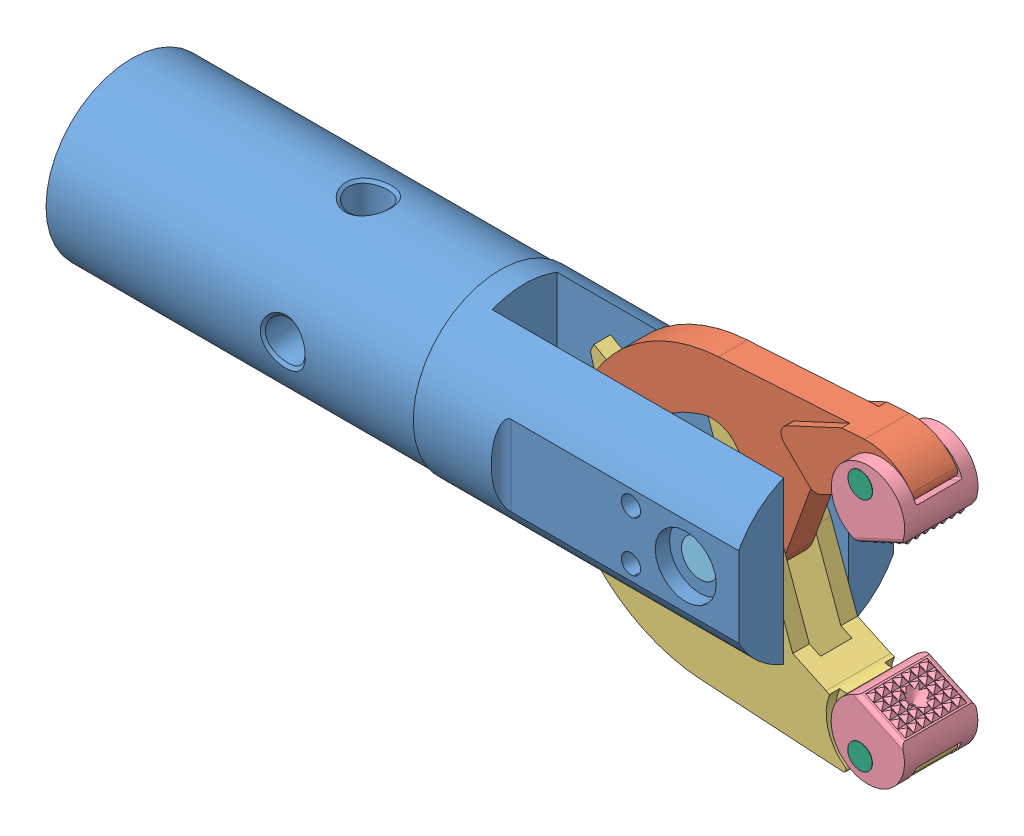
SolidWorks assembly Ensamblaje 2 Pieza 2 Tarea 2, configuration Predeterminado. Lengths in mm.
Overall size (215.83 114.08 45.21).
8 component instances, 6 part files, 19 mates.
Components (placement in the parent):
- T02 EJER02 Body-1: T02 EJER02 Body [Default] at origin size (177.75 45.21 45.21)
- T02 EJER02 Arm1-1: T02 EJER02 Arm1 [Default] at (-13.7795 0 0) x (-0.906308 -0.422618 0) z (0 0 -1) size (103 45.53 11.68)
- T02 EJER02 Arm2-1: T02 EJER02 Arm2 [Default] at (-13.7795 0 0) x (-0.906308 0.422618 0) z (0 0 1) size (103 45.53 16.81)
- T02 EJER02 Grip-1: T02 EJER02 Grip [Default] at (22.9957 26.313 -0.0254) x (0 0 -1) z (0.906308 0.422618 0) size (19.05 17.93 19.05)
- T02 EJER02 Large_Pin-1: T02 EJER02 Large_Pin [Default] at (-13.7795 0 -0.127) size (9.53 9.53 32.77)
- T02 EJER02 Small_Pin-1: T02 EJER02 Small_Pin [Default] at (21.0098 30.5717 0.1746) size (6.35 6.35 19.16)
- T02 EJER02 Grip-2: T02 EJER02 Grip [Default] at (22.9957 -26.313 0.0254) x (0 0 1) z (0.906308 -0.422618 0) size (19.05 17.93 19.05)
- T02 EJER02 Small_Pin-2: T02 EJER02 Small_Pin [Default] at (21.0098 -30.5717 0.2254) size (6.35 6.35 19.16)
Mates (geometry in assembly coordinates):
- Coincidente1: coordinate: point of T02 EJER02 Body-1
- Coincidente4: coincident anti-aligned: plane of T02 EJER02 Body-1 through (-75.692 -22.606 8.4074) normal (0 0 -1); plane of T02 EJER02 Arm2-1 through (21.091 -63.9042 8.4074) normal (0 0 1)
- Concéntrica4: concentric aligned: circle of T02 EJER02 Body-1; circle of T02 EJER02 Arm2-1
- Concéntrica9: concentric anti-aligned: cylinder of T02 EJER02 Arm1-1 through (-13.7795 0 5.842) axis (0 0 -1) radius 4.7688; cylinder of T02 EJER02 Arm2-1 through (-13.7795 0 -8.4074) axis (0 0 1) radius 4.7688
- Ancho8: width aligned: plane of T02 EJER02 Arm2-1 through (21.091 -63.9042 4.0894) normal (0 0 -1); plane of T02 EJER02 Arm1-1 through (21.091 -63.9042 -4.0894) normal (0 0 1); plane of T02 EJER02 Arm2-1 through (21.091 63.9042 -3.7592) normal (0 0 -1); plane of T02 EJER02 Arm1-1 through (21.091 63.9042 3.7592) normal (0 0 1)
- Ancho9: width aligned: plane of T02 EJER02 Body-1 through (-13.7795 0 -16.3576) normal (0 0 -1); plane of T02 EJER02 Large_Pin-1 through (-13.7795 0 16.3576) normal (0 0 1); plane of T02 EJER02 Body-1 through (-13.7795 0 -16.383) normal (0 0 -1); plane of T02 EJER02 Large_Pin-1 through (-13.7795 0 16.383) normal (0 0 1)
- Concéntrica10: concentric anti-aligned: circle of T02 EJER02 Body-1; circle of T02 EJER02 Large_Pin-1
- Ancho10: width anti-aligned: plane of T02 EJER02 Arm1-1 through (13.1554 16.7638 5.842) normal (0 0 1); plane of T02 EJER02 Grip-1 through (13.1554 16.7638 -5.842) normal (0 0 -1); plane of T02 EJER02 Arm1-1 through (56.3504 52.3762 5.9944) normal (0 0 -1); plane of T02 EJER02 Grip-1 through (60.7516 42.9379 -5.9944) normal (0 0 1)
- Concéntrica11: concentric anti-aligned: circle of T02 EJER02 Arm1-1; circle of T02 EJER02 Grip-1
- Ancho11: width aligned: plane of T02 EJER02 Arm2-1 through (13.1554 -16.7638 -5.842) normal (0 0 -1); plane of T02 EJER02 Grip-2 through (13.1554 -16.7638 5.842) normal (0 0 1); plane of T02 EJER02 Arm2-1 through (60.7516 -42.9379 5.9944) normal (0 0 -1); plane of T02 EJER02 Grip-2 through (56.3504 -52.3762 -5.9944) normal (0 0 1)
- Concéntrica12: concentric aligned: circle of T02 EJER02 Arm2-1; circle of T02 EJER02 Grip-2
- Paralelo3: parallel anti-aligned: plane of T02 EJER02 Arm2-1 through (13.9861 -21.7754 -8.4074) normal (0.422618 0.906308 0); plane of T02 EJER02 Grip-2 through (60.7516 -42.9379 -5.9944) normal (-0.422618 -0.906308 0)
- Ángulo4: planar angle = 0.436332 rad aligned: line of T02 EJER02 Grip-2 through (32.1519 -23.6883 9.5504) axis (-0.906308 0.422618 0); line of T02 EJER02 Body-1 through (0 -20.9844 8.4074) axis (-1 0 0)
- Paralelo6: parallel anti-aligned: plane of T02 EJER02 Arm1-1 through (13.9861 21.7754 3.7592) normal (0.422618 -0.906308 0); plane of T02 EJER02 Grip-1 through (60.7516 42.9379 5.9944) normal (-0.422618 0.906308 0)
- Ángulo5: planar angle = 0.436332 rad aligned: line of T02 EJER02 Grip-1 through (32.1519 23.6883 -9.5504) axis (-0.906308 -0.422618 0); line of T02 EJER02 Body-1 through (0 20.9844 -8.4074) axis (-1 0 0)
- Ancho12: width aligned: plane of T02 EJER02 Grip-2 through (22.9957 -26.313 -9.4996) normal (0 0 -1); plane of T02 EJER02 Small_Pin-2 through (22.9957 -26.313 9.5504) normal (0 0 1); plane of T02 EJER02 Grip-2 through (21.0098 -30.5717 -9.5536) normal (0 0 -1); plane of T02 EJER02 Small_Pin-2 through (21.0098 -30.5717 9.6044) normal (0 0 1)
- Concéntrica13: concentric aligned: circle of T02 EJER02 Grip-2; circle of T02 EJER02 Small_Pin-2
- Ancho13: width: plane of T02 EJER02 Grip-1 through (22.9957 26.313 -9.5504) normal (0 0 -1); plane of T02 EJER02 Small_Pin-1 through (22.9957 26.313 9.4996) normal (0 0 1); plane of T02 EJER02 Grip-1 through (21.8196 53.2449 -9.6044) normal (0 0 -1); plane of T02 EJER02 Small_Pin-1 through (21.8196 53.2449 9.5536) normal (0 0 1)
- Concéntrica14: concentric anti-aligned: circle of T02 EJER02 Grip-1; circle of T02 EJER02 Small_Pin-1
